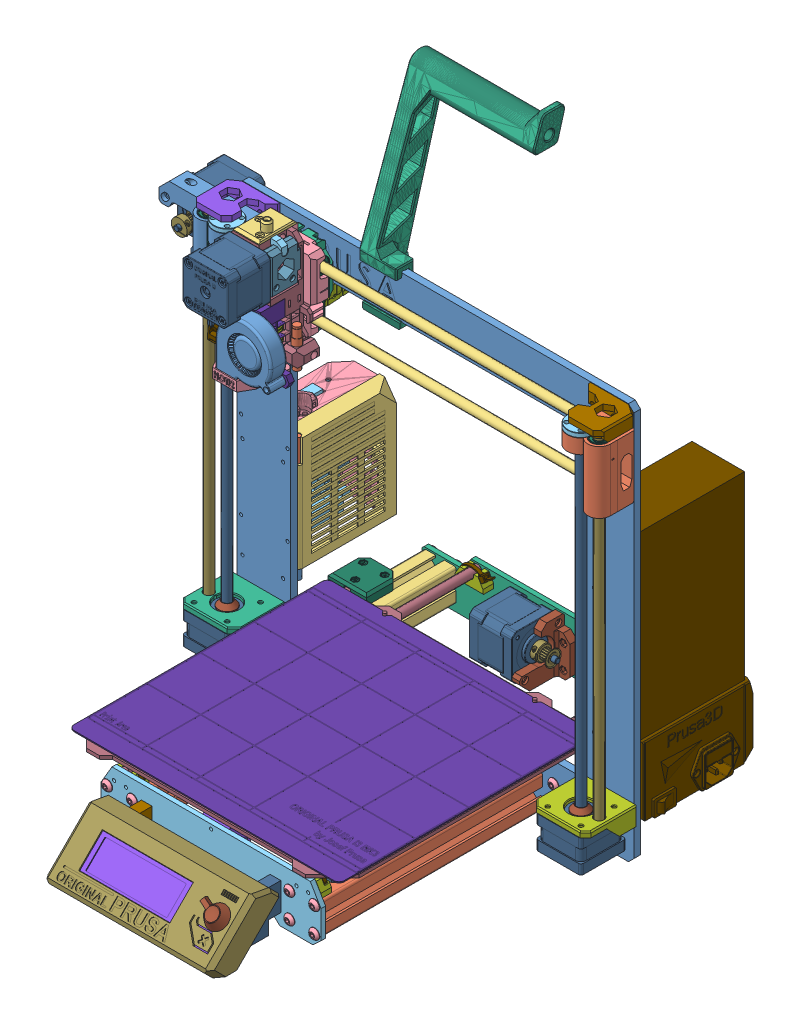
SolidWorks assembly Prusa i3 MK3, configuration Default. Lengths in mm.
Overall size (428.7 559.98 435.12).
133 component instances, 60 part files, 144 mates.
Components (placement in the parent):
- Frame Assembly-1: Frame Assembly [Default] at (46.7331 -29.8101 -38.614) size (370 375 345.6)
  - i3 MK3 Frame-1: i3 MK3 Frame [Default] at (-79.4742 52.1894 268.1135) size (370 370 6.25)
  - Long Extrusion-1: Long Extrusion [Default] at (190.5258 68.6894 274.3635) size (30 30 205)
  - Long Extrusion-2: Long Extrusion [Default] at (20.5258 68.6894 274.3635) size (30 30 205)
  - Short Extrusion-1: Short Extrusion [Default] at (-16.4742 68.6894 148.1135) size (30 30 120)
  - Short Extrusion-2: Short Extrusion [Default] at (227.5258 68.6894 148.1135) size (30 30 120)
  - M5-16 Caphead Screw-1: M5-16 Caphead Screw [92095A212] at (239.1258 57.0894 277.1135) size (9.5 9.5 19.24)
  - M5-16 Caphead Screw-2: M5-16 Caphead Screw [92095A212] at (8.9287 80.3027 486.3635) size (9.5 9.5 19.24)
  - M5-16 Caphead Screw-3: M5-16 Caphead Screw [92095A212] at (202.1295 80.303 486.3635) size (9.5 9.5 19.24)
  - M5-16 Caphead Screw-4: M5-16 Caphead Screw [92095A212] at (178.9311 80.3021 486.3635) size (9.5 9.5 19.24)
  - M5-16 Caphead Screw-5: M5-16 Caphead Screw [92095A212] at (215.9258 80.2894 277.1135) size (9.5 9.5 19.24)
  - M5-16 Caphead Screw-6: M5-16 Caphead Screw [92095A212] at (8.9258 57.0894 486.3635) size (9.5 9.5 19.24)
  - M5-16 Caphead Screw-7: M5-16 Caphead Screw [92095A212] at (178.9324 57.0896 486.3635) size (9.5 9.5 19.24)
  - M5-16 Caphead Screw-8: M5-16 Caphead Screw [92095A212] at (239.1258 80.2894 277.1135) size (9.5 9.5 19.24)
  - M5-16 Caphead Screw-9: M5-16 Caphead Screw [92095A212] at (202.1324 57.0896 486.3635) size (9.5 9.5 19.24)
  - M5-16 Caphead Screw-10: M5-16 Caphead Screw [92095A212] at (32.1258 57.0894 486.3635) size (9.5 9.5 19.24)
  - M5-16 Caphead Screw-11: M5-16 Caphead Screw [92095A212] at (32.127 80.3019 486.3635) size (9.5 9.5 19.24)
  - M5-16 Caphead Screw-12: M5-16 Caphead Screw [92095A212] at (-4.8742 80.2894 277.1135) size (9.5 9.5 19.24)
  - M5-16 Caphead Screw-13: M5-16 Caphead Screw [92095A212] at (-4.8742 57.0894 277.1135) size (9.5 9.5 19.24)
  - M5-16 Caphead Screw-14: M5-16 Caphead Screw [92095A212] at (-28.0742 80.2894 277.1135) size (9.5 9.5 19.24)
  - M5-16 Caphead Screw-15: M5-16 Caphead Screw [92095A212] at (-28.0742 57.0894 277.1135) size (9.5 9.5 19.24)
  - M5-16 Caphead Screw-16: M5-16 Caphead Screw [92095A212] at (215.9258 57.0894 277.1135) size (9.5 9.5 19.24)
  - M5-16 Caphead Screw-17: M5-16 Caphead Screw [92095A212] at (215.9258 80.2894 141.1135) x (1 0 0) z (0 0 -1) size (9.5 9.5 19.24)
  - M5-16 Caphead Screw-18: M5-16 Caphead Screw [92095A212] at (32.1258 80.2894 265.3635) x (1 0 0) z (0 0 -1) size (9.5 9.5 19.24)
  - M5-16 Caphead Screw-19: M5-16 Caphead Screw [92095A212] at (202.1258 80.2894 265.3635) x (1 0 0) z (0 0 -1) size (9.5 9.5 19.24)
  - M5-16 Caphead Screw-20: M5-16 Caphead Screw [92095A212] at (178.9258 80.2894 265.3635) x (1 0 0) z (0 0 -1) size (9.5 9.5 19.24)
  - M5-16 Caphead Screw-21: M5-16 Caphead Screw [92095A212] at (215.926 57.0893 141.1135) x (1 0 0) z (0 0 -1) size (9.5 9.5 19.24)
  - M5-16 Caphead Screw-22: M5-16 Caphead Screw [92095A212] at (8.9258 57.0894 265.3635) x (1 0 0) z (0 0 -1) size (9.5 9.5 19.24)
  - M5-16 Caphead Screw-23: M5-16 Caphead Screw [92095A212] at (8.9258 80.2894 265.3635) x (1 0 0) z (0 0 -1) size (9.5 9.5 19.24)
  - M5-16 Caphead Screw-24: M5-16 Caphead Screw [92095A212] at (239.1258 80.2894 141.1135) x (1 0 0) z (0 0 -1) size (9.5 9.5 19.24)
  - M5-16 Caphead Screw-25: M5-16 Caphead Screw [92095A212] at (239.1259 57.0892 141.1135) x (1 0 0) z (0 0 -1) size (9.5 9.5 19.24)
  - M5-16 Caphead Screw-26: M5-16 Caphead Screw [92095A212] at (-4.8712 80.276 141.1135) x (1 0 0) z (0 0 -1) size (9.5 9.5 19.24)
  - M5-16 Caphead Screw-27: M5-16 Caphead Screw [92095A212] at (-28.0743 80.2892 141.1135) x (1 0 0) z (0 0 -1) size (9.5 9.5 19.24)
  - M5-16 Caphead Screw-28: M5-16 Caphead Screw [92095A212] at (-28.072 57.0752 141.1135) x (1 0 0) z (0 0 -1) size (9.5 9.5 19.24)
  - M5-16 Caphead Screw-29: M5-16 Caphead Screw [92095A212] at (-4.874 57.0894 141.1135) x (1 0 0) z (0 0 -1) size (9.5 9.5 19.24)
  - M5-16 Caphead Screw-30: M5-16 Caphead Screw [92095A212] at (178.9258 57.0894 265.3635) x (1 0 0) z (0 0 -1) size (9.5 9.5 19.24)
  - M5-16 Caphead Screw-31: M5-16 Caphead Screw [92095A212] at (202.1258 57.0894 265.3635) x (1 0 0) z (0 0 -1) size (9.5 9.5 19.24)
  - M5-16 Caphead Screw-32: M5-16 Caphead Screw [92095A212] at (32.1258 57.0894 265.3635) x (1 0 0) z (0 0 -1) size (9.5 9.5 19.24)
  - MK3 Front Plate-1: MK3 Front Plate [Default] at (105.5324 47.1896 479.3635) x (-1 0 0) z (0 0 1) size (205 50 4.25)
  - MK3 Rear Plate-1: MK3 Rear Plate [Default] at (105.526 50.1894 143.8635) size (278 50 4.25)
- y-rod-holder(R2)-1: y-rod-holder(R2) [Default] at (67.2591 53.8793 109.4995) x (-1 0 0) z (0 0 1) size (26 13.5 10)
- y-rod-holder(R2)-2: y-rod-holder(R2) [Default] at (237.2591 53.8793 109.4995) x (-1 -0.000001 0) z (0 0 1) size (26 13.5 10)
- y-rod-holder(R2)-3: y-rod-holder(R2) [Default] at (67.2588 53.8793 440.7495) x (1 0.000003 0) z (0 0 -1) size (26 13.5 10)
- y-rod-holder(R2)-4: y-rod-holder(R2) [Default] at (237.2655 53.8796 440.7495) x (1 0 0) z (0 0 -1) size (26 13.5 10)
- y-belt-idler(R2)-1: y-belt-idler(R2) [Default] at (152.2622 27.3871 440.7495) x (-1 -0.000001 0) z (-0.000001 1 0) size (25 20 35)
- Idler Roller, flat-1: Idler Roller, flat [Default] at (147.9121 49.8871 426.7495) x (0 0 -1) z (1 0.000001 0) size (18 18 8.83)
- NEMA-17 40mm PR-1: NEMA-17 40mm PR [По умолчанию] at (99.2666 46.3725 130.4995) x (0 0 -1) z (0 -1 0) size (42.3 62 51.35)
- y-motor-holder(R2)-1: y-motor-holder(R2) [Default] at (152.2666 20.3725 110.9995) x (-1 0 0) z (0 1 0) size (19 42 47)
- PULLEY_GT2_16T-1: PULLEY_GT2_16T [Default] at (148.5591 46.3725 130.4995) x (0 -0.177583 0.984106) z (-1 0 0) size (14.7 14.7 14.3)
- Y-Smooth Rod-1: Y-Smooth Rod [Default] at (67.2588 64.3793 110.7495) size (8 8 330)
- Frog Assembly-1: Frog Assembly [Default] at (70.8506 199.1097 499.2992) x (1 0 0) z (0 0 -1) size (227 34.1 222)
  - i3 MK3 Frog-1: i3 MK3 Frog [Default] at (-100.0918 124.8902 356.7011) size (227 4.25 222)
  - LM8UU-1: LM8UU [Default] at (166.4082 134.7303 172.4511) x (0 0 -1) z (0.49499 0.868899 0) size (24 15 15)
  - LM8UU-2: LM8UU [Default] at (-3.5918 134.7303 205.9511) x (0 0 -1) z (0.957162 -0.289554 0) size (24 15 15)
  - LM8UU-3: LM8UU [Default] at (-3.5918 134.7303 135.9511) x (0 0 -1) z (-0.936768 -0.349951 0) size (24 15 15)
  - y-belt-holder(R2)-1: y-belt-holder(R2) [Default] at (88.4082 141.6402 171.2011) x (0 -1 0) z (-1 0 0) size (23.5 48 14)
  - U Bolt-1: U Bolt [Default] at (166.4082 118.7303 171.7011) size (23.09 26.7 3.46)
  - U Bolt-2: U Bolt [Default] at (-3.5918 118.7303 136.7011) size (23.09 26.7 3.46)
  - U Bolt-3: U Bolt [Default] at (-3.5918 118.7303 206.7011) size (23.09 26.7 3.46)
- Y-Smooth Rod-2: Y-Smooth Rod [Default] at (237.2655 64.3796 110.7495) size (8 8 330)
- Y Holder Ziptie-1: Y Holder Ziptie [Default] at (237.2655 53.8796 434.0495) size (30.19 10 6)
- Y Holder Ziptie-2: Y Holder Ziptie [Default] at (237.1042 53.8796 116.1995) x (1 0.000001 0) z (0 0 1) size (30.19 10 6)
- Y Holder Ziptie-3: Y Holder Ziptie [Default] at (67.4135 53.8793 434.0495) x (-1 -0.000003 0) z (0 0 -1) size (30.19 10 6)
- Y Holder Ziptie-4: Y Holder Ziptie [Default] at (67.2591 53.8793 116.1995) x (-1 0 0) z (0 0 -1) size (30.19 10 6)
- x-end-motor(R2)-1: x-end-motor(R2) [Default] at (-29.7411 380.6793 265.0495) x (0 0 1) z (0 -1 0) size (36.16 82.62 62.53)
- x-end-idler(R2)-1: x-end-idler(R2) [Default] at (355.2589 380.6793 265.0495) x (0 0 1) z (0 -1 0) size (36.12 40.12 58)
- X-Smooth Rod-1: X-Smooth Rod [Default] at (-36.7411 374.6793 250.0495) x (0 0 -1) z (1 0 0) size (8 8 370)
- X-Smooth Rod-2: X-Smooth Rod [Default] at (-36.7411 329.6793 250.0495) x (0 0 -1) z (1 0 0) size (8 8 370)
- LM8UU-1: LM8UU [Default] at (-29.7411 368.6793 265.0495) x (0 1 0) z (0 0 1) size (24 15 15)
- LM8UU-2: LM8UU [Default] at (334.2589 334.6793 265.0495) x (0 1 0) z (0 0 1) size (24 15 15)
- LM8UU-3: LM8UU [Default] at (-29.7411 335.2793 265.0495) x (0 1 0) z (0 0 1) size (24 15 15)
- LM8UU-4: LM8UU [Default] at (334.2589 368.6793 265.0495) x (0 1 0) z (-0.546944 0 0.837169) size (24 15 15)
- LM8UU-5: LM8UU [Default] at (24.8458 374.6793 250.0495) size (24 15 15)
- LM8UU-6: LM8UU [Default] at (37.3458 329.6793 250.0495) size (24 15 15)
- LM8UU-7: LM8UU [Default] at (48.8458 374.6793 250.0495) size (24 15 15)
- NEMA-17 40mm PR-2: NEMA-17 40mm PR [По умолчанию] at (-61.7411 350.4293 201.5495) x (1 0 0) z (0 -1 0) size (42.3 62 51.35)
- PULLEY_GT2_16T-2: PULLEY_GT2_16T [Default] at (-61.7411 350.4293 254.7495) x (0.994167 -0.107852 0) z (0 0 1) size (14.7 14.7 14.3)
- x-carriage(R2)-1: x-carriage(R2) [Default] at (21.3458 329.6793 262.0495) x (-1 0 0) z (0 0 -1) size (52 90 15)
- Idler Roller, flat-2: Idler Roller, flat [Default] at (318.7589 350.4293 246.6995) size (18 18 8.83)
- Z_NUT-1: Z_NUT [Default] at (-12.7411 384.6793 265.0495) x (0.707107 0 -0.707107) z (0.707107 0 0.707107) size (25 10 25)
- Z_NUT-2: Z_NUT [Default] at (317.2589 384.6793 265.0495) x (0.707107 0 0.707107) z (-0.707107 0 0.707107) size (25 10 25)
- z-axis-bottom-left(R2)-1: z-axis-bottom-left(R2) [Default] at (-45.7411 74.1793 235.7495) x (0 0 1) z (0 -1 0) size (50 52.5 36)
- z-axis-bottom-right(R2)-1: z-axis-bottom-right(R2) [Default] at (337.2589 74.1793 235.7495) x (0 0 1) z (0 -1 0) size (50 52.5 36)
- z-axis-top-left(R2)-1: z-axis-top-left(R2) [Default] at (-42.7411 392.1793 235.7495) x (0 0 1) z (0 -1 0) size (38 45 16)
- z-axis-top-right(R2)-1: z-axis-top-right(R2) [Default] at (337.2589 392.1793 235.7495) x (0 0 1) z (0 -1 0) size (38 45 16)
- MOTOR_NEMA17_W_THREADED_SHAFT-1: MOTOR_NEMA17_W_THREADED_SHAFT [Default] at (-12.7411 54.1793 265.0495) x (0 0 -1) z (0 1 0) size (47.3 42.3 350)
- MOTOR_NEMA17_W_THREADED_SHAFT-2: MOTOR_NEMA17_W_THREADED_SHAFT [Default] at (317.2589 54.1793 265.0495) x (0 0 -1) z (0 1 0) size (47.3 42.3 350)
- z-screw-cover-1: z-screw-cover [Default] at (-12.7411 71.1793 265.0495) x (1 0 0) z (0 1 0) size (16 16 5)
- z-screw-cover-2: z-screw-cover [Default] at (317.2589 71.1793 265.0495) x (1 0 0) z (0 1 0) size (16 16 5)
- Z-Smooth Rod-1: Z-Smooth Rod [Default] at (-29.7411 389.1793 265.0495) x (1 0 0) z (0 -1 0) size (8 8 320)
- Z-Smooth Rod-2: Z-Smooth Rod [Default] at (334.2589 389.1793 265.0495) x (1 0 0) z (0 -1 0) size (8 8 320)
- Extruder Assembly-1: Extruder Assembly [Default] at (24.1055 296.0339 201.1728) size (76.41 114.5 76)
  - extruder-body(R2)-1: extruder-body(R2) [Default] at (14.2402 58.6454 60.8767) x (-1 0 0) z (0 0 -1) size (63.5 95 30.5)
  - extruder-idler(R2)-1: extruder-idler(R2) [Default] at (14.2402 58.6454 59.3767) x (0 0 1) z (-1 0 0) size (28 34 17)
  - idler pulley shaft-1: idler pulley shaft [Default] at (18.2402 85.6454 62.1267) size (3 3 24)
  - NEMA-17 40mm PR-1: NEMA-17 40mm PR [По умолчанию] at (10.2402 85.6454 131.3767) x (-1 0 0) z (0 -1 0) size (42.3 62 51.35)
  - E3D V6-1: E3D V6 [Default] at (14.2402 48.5454 77.8767) x (1 0 0) z (0 -1 0) size (21.69 25.84 58.6)
  - extruder-cover(R2)-1: extruder-cover(R2) [Default] at (14.2402 58.6454 60.8767) x (-1 0 0) z (0 0 -1) size (75.15 49.75 23.94)
  - Noctua-NF-A4x10-1: Noctua-NF-A4x10 [Default] at (-12.2589 37.0799 80.8112) x (0 -1 0) z (-1 0 0) size (40.06 40.06 12.26)
  - FAN_5015_BLOWER-1: FAN_5015_BLOWER [Default] at (31.7402 38.1454 116.2767) x (0 -1 0) z (1 0 0) size (51.75 17.19 52.1)
  - PINDA Probe-1: PINDA Probe [Default] at (37.2402 32.9116 72.8767) x (1 0 0) z (0 -1 0) size (7.8 7.8 35.75)
  - filament-sensor-cover-1: filament-sensor-cover [Default] at (14.2402 58.6454 60.8767) x (-1 0 0) z (0 0 -1) size (24 11.5 36)
  - nozzle-fan-1: nozzle-fan [Default] at (14.2402 58.6454 65.3767) x (-1 0 0) z (0 0 -1) size (47.83 17 42)
  - extruder-idler-plug-1: extruder-idler-plug [Default] at (13.8402 58.6454 59.3767) x (-1 0 0) z (0 0 -1) size (10.6 10.3 5.6)
- x-carriage-back(R2)-1: x-carriage-back(R2) [Default] at (38.3458 354.6793 262.1495) x (-1 0 0) z (0 0 -1) size (52 73.5 8)
- cable-holder-1: cable-holder [Default] at (38.3458 354.6793 263.0495) x (-1 0 0) z (0 0 -1) size (10 17.91 39.5)
- LCD Assembly-1: LCD Assembly [Default] at (106.2916 -100.65 474.1347) x (1 0 0) z (0 0.707107 0.707107) size (155 84.29 80.03)
  - LCD Board-1: LCD Board [Default] at (45.5138 89.6171 111.3378) size (150 63 29.71)
  - lcd-supports1-1: lcd-supports1 [Default] at (-9.0362 59.8671 105.6378) x (0 -0.707107 0.707107) z (-1 0 0) size (65.69 47.48 20)
  - lcd-supports2-1: lcd-supports2 [Default] at (110.9738 59.8671 105.6378) x (0 -0.707107 0.707107) z (-1 0 0) size (65.69 47.48 10)
  - LCD-KNOB-1: LCD-KNOB [Default] at (104.2929 89.8433 126.2378) x (-0.386654 -0.922225 0) z (0 0 1) size (20 27.64 8.79)
  - LCD-cover-ORIGINAL-MK3(R2)-1: LCD-cover-ORIGINAL-MK3(R2) [Default] at (45.2638 108.0671 124.7378) x (1 0 0) z (0 0 -1) size (155 70 26.06)
- Headbed Assembly-1: Headbed Assembly [Default] at (88.2608 -72.955 114.9048) size (253.8 13.6 281.4)
  - MK52 Bed-1: MK52 Bed [Default] at (-64.502 153.1745 327.7347) size (253.8 6 264.25)
  - 6x6x3t spacer-1: 6x6x3t spacer [Default] at (62.498 147.1745 212.6933) size (6 6 6)
  - 6x6x3t spacer-2: 6x6x3t spacer [Default] at (62.498 147.1745 107.6933) size (6 6 6)
  - 6x6x3t spacer-3: 6x6x3t spacer [Default] at (-47.502 147.1745 317.6933) size (6 6 6)
  - 6x6x3t spacer-4: 6x6x3t spacer [Default] at (-47.502 147.1745 107.6933) x (0.97497 0 -0.222336) z (0.222336 0 0.97497) size (6 6 6)
  - 6x6x3t spacer-5: 6x6x3t spacer [Default] at (167.498 147.1745 317.6933) size (6 6 6)
  - 6x6x3t spacer-6: 6x6x3t spacer [Default] at (167.498 147.1745 212.6933) size (6 6 6)
  - 6x6x3t spacer-7: 6x6x3t spacer [Default] at (167.498 147.1745 107.6933) x (0.999855 0 0.017002) z (-0.017002 0 0.999855) size (6 6 6)
  - 6x6x3t spacer-8: 6x6x3t spacer [Default] at (62.498 147.1745 317.6933) size (6 6 6)
  - 6x6x3t spacer-9: 6x6x3t spacer [Default] at (-47.502 147.1745 212.6933) size (6 6 6)
  - heatbed-cable-cover top-1: heatbed-cable-cover top [Default] at (-46.0021 152.1745 93.2347) x (1 0 0) z (0 1 0) size (36 32 8.6)
  - heatbed-cable-cover bottom-1: heatbed-cable-cover bottom [Default] at (-46.0021 157.6745 113.2347) x (-1 0 0) z (0 -1 0) size (30 16.5 6)
  - SS Sheet-1: SS Sheet [Default] at (-63.6476 156.1745 335.43) size (252 1.01 241)
- PSU-1: PSU [Default] at (284.7589 53.8793 227.9995) x (0 0 -1) z (1 0 0) size (103 233 79.05)
- Einsy-hinges2-1: Einsy-hinges2 [Default] at (18.6589 86.1793 224.4995) x (0 0 -1) z (0 1 0) size (7.8 13.8 17)
- Einsy-hinges1-1: Einsy-hinges1 [Default] at (12.6589 201.1793 224.4995) x (0 0 -1) z (0 -1 0) size (7.4 13.4 28)
- einsey-doors-1: einsey-doors [Default] at (17.1589 201.6793 136.9995) x (0 -1 0) z (-1 0 0) size (105.5 92 16.29)
- Einsy-base-1: Einsy-base [Default] at (-32.8339 200.6796 229.4995) x (-0.000069 -1 0) z (1 -0.000069 0) size (127.5 92 38)
- Einsy_Rambo-1: Einsy_Rambo [Default] at (-23.241 175.7001 163.4002) x (-0.000069 -1 0) z (1 -0.000069 0) size (108.28 71 21.5)
- Spool-holder-1: Spool-holder [Default] at (86.205 379.5108 561.5962) x (0 0 -1) z (1 0 0) size (72.27 192.64 120.6)
Mates (geometry in assembly coordinates):
- Coincident1: coincident anti-aligned: plane of Frame Assembly-1/MK3 Front Plate-1 through (152.2655 17.3796 440.7495) normal (0 0 -1); plane of y-rod-holder(R2)-3 through (54.2588 53.8793 440.7495) normal (0 0 1)
- Coincident2: coincident anti-aligned: plane of Frame Assembly-1/MK3 Front Plate-1 through (152.2655 17.3796 440.7495) normal (0 0 -1); plane of y-rod-holder(R2)-4 through (224.2655 53.8796 440.7495) normal (0 0 1)
- Concentric1: concentric anti-aligned: circle of Frame Assembly-1/MK3 Front Plate-1; cone of y-rod-holder(R2)-4 through (242.7655 57.3796 440.7495) axis (0 0 -1)
- Concentric2: concentric aligned: circle of Frame Assembly-1/MK3 Front Plate-1; circle of y-rod-holder(R2)-4
- Concentric3: concentric aligned: circle of Frame Assembly-1/MK3 Front Plate-1; circle of y-rod-holder(R2)-3
- Concentric4: concentric aligned: circle of Frame Assembly-1/MK3 Front Plate-1; circle of y-rod-holder(R2)-3
- Coincident4: coincident anti-aligned: plane of Frame Assembly-1/MK3 Rear Plate-1 through (152.2591 20.3793 109.4995) normal (0 0 1); plane of y-rod-holder(R2)-2 through (250.2591 53.8794 109.4995) normal (0 0 -1)
- Coincident5: coincident anti-aligned: plane of Frame Assembly-1/MK3 Rear Plate-1 through (152.2591 20.3793 109.4995) normal (0 0 1); plane of y-rod-holder(R2)-1 through (80.2591 53.8793 109.4995) normal (0 0 -1)
- Concentric5: concentric anti-aligned: circle of Frame Assembly-1/MK3 Rear Plate-1; cylinder of y-rod-holder(R2)-1 through (61.7591 57.3793 118.4995) axis (0 0 -1) radius 1.6
- Concentric9: concentric aligned: cylinder of Frame Assembly-1/MK3 Rear Plate-1 through (231.7591 57.3793 109.4995) axis (0 0 -1) radius 1.5; circle of y-rod-holder(R2)-2
- Concentric10: concentric aligned: cylinder of Frame Assembly-1/MK3 Rear Plate-1 through (242.7591 57.3793 109.4995) axis (0 0 -1) radius 1.5; circle of y-rod-holder(R2)-2
- Parallel1: parallel aligned: plane of Frame Assembly-1/MK3 Rear Plate-1 through (245.2591 67.3793 109.4995) normal (0 1 0); plane of y-rod-holder(R2)-1 through (80.2591 65.8793 109.4995) normal (0 1 0)
- Coincident7: coincident anti-aligned: plane of y-belt-idler(R2)-1 through (152.2622 27.3871 440.7495) normal (-1 -0.000001 0); plane of Idler Roller, flat-1 through (152.2621 49.8871 426.7495) normal (1 0.000001 0)
- Concentric11: concentric anti-aligned: cylinder of y-belt-idler(R2)-1 through (144.2621 49.8871 426.7495) axis (-1 -0.000001 0) radius 3.1; cylinder of Idler Roller, flat-1 through (147.9111 49.8871 426.7495) axis (1 0.000001 0) radius 2.5
- Coincident8: coincident anti-aligned: plane of Frame Assembly-1/MK3 Front Plate-1 through (152.2655 17.3796 440.7495) normal (0 0 -1); plane of y-belt-idler(R2)-1 through (164.7622 32.3871 440.7495) normal (0 0 1)
- Concentric12: concentric aligned: circle of Frame Assembly-1/MK3 Front Plate-1; circle of y-belt-idler(R2)-1
- Concentric13: concentric anti-aligned: cylinder of Frame Assembly-1/MK3 Front Plate-1 through (152.2622 37.387 444.9995) axis (0 0 -1) radius 1.5; circle of y-belt-idler(R2)-1
- Coincident9: coincident anti-aligned: plane of NEMA-17 40mm PR-1 through (139.2666 46.3725 130.4995) normal (1 0 0); plane of y-motor-holder(R2)-1 through (139.2666 20.3725 109.4995) normal (-1 0 0)
- Concentric14: concentric aligned: circle of NEMA-17 40mm PR-1; cylinder of y-motor-holder(R2)-1 through (148.2666 61.8725 114.9995) axis (-1 0 0) radius 3.1
- Concentric15: concentric aligned: circle of NEMA-17 40mm PR-1; circle of y-motor-holder(R2)-1
- Coincident10: coincident anti-aligned: plane of Frame Assembly-1/MK3 Rear Plate-1 through (152.2591 20.3793 109.4995) normal (0 0 1); plane of y-motor-holder(R2)-1 through (158.2666 20.3725 109.4995) normal (0 0 -1)
- Concentric16: concentric anti-aligned: circle of Frame Assembly-1/MK3 Rear Plate-1; cylinder of y-motor-holder(R2)-1 through (152.2666 27.3725 122.9995) axis (0 0 -1) radius 1.6
- Parallel2: parallel aligned: plane of Frame Assembly-1/MK3 Rear Plate-1 through (245.2591 67.3793 109.4995) normal (0 1 0); plane of y-motor-holder(R2)-1 through (158.2666 67.3725 109.4995) normal (0 1 0)
- Concentric19: concentric anti-aligned: cylinder of NEMA-17 40mm PR-1 through (161.2666 46.3725 130.4995) axis (-1 0 0) radius 2.5; cylinder of PULLEY_GT2_16T-1 through (142.2591 46.3725 130.4995) axis (1 0 0) radius 2.5
- Coincident15: coincident aligned: plane of Frame Assembly-1/MK3 Rear Plate-1 through (152.2591 20.3793 105.2495) normal (1 0 0); plane of PULLEY_GT2_16T-1 through (152.2591 46.3725 130.4995) normal (1 0 0)
- Concentric20: concentric anti-aligned: cylinder of y-rod-holder(R2)-3 through (67.2588 64.3793 429.7495) axis (0 0 1) radius 4; cylinder of Y-Smooth Rod-1 through (67.2588 64.3793 440.7495) axis (0 0 -1) radius 4
- Coincident16: coincident anti-aligned: plane of Frame Assembly-1/MK3 Front Plate-1 through (152.2655 17.3796 440.7495) normal (0 0 -1); plane of Y-Smooth Rod-1 through (67.2588 64.3793 440.7495) normal (0 0 1)
- Concentric21: concentric anti-aligned: cylinder of y-rod-holder(R2)-4 through (237.2655 64.3796 429.7495) axis (0 0 1) radius 4; cylinder of Y-Smooth Rod-2 through (237.2655 64.3796 440.7495) axis (0 0 -1) radius 4
- Coincident17: coincident anti-aligned: plane of Frame Assembly-1/MK3 Front Plate-1 through (152.2655 17.3796 440.7495) normal (0 0 -1); plane of Y-Smooth Rod-2 through (237.2655 64.3796 440.7495) normal (0 0 1)
- Concentric22: concentric aligned: cylinder of Y-Smooth Rod-1 through (67.2588 64.3793 440.7495) axis (0 0 -1) radius 4; cylinder of Frog Assembly-1/LM8UU-3 through (67.2588 64.3793 317.6586) axis (0 0 -1) radius 4
- Parallel3: parallel aligned: plane of Frame Assembly-1/i3 MK3 Frame-1 through (-32.7411 58.8793 235.7495) normal (0 1 0); plane of Frog Assembly-1/i3 MK3 Frog-1 through (-29.2412 74.2195 142.5981) normal (0 1 0)
- Tangent2: tangent aligned: cylinder of Y-Smooth Rod-2 through (237.2655 64.3796 440.7495) axis (0 0 -1) radius 4; cylinder of Y Holder Ziptie-1 through (237.3428 54.524 435.5495) axis (0 0 -1) radius 13.8558
- Coincident20: coincident anti-aligned: plane of y-rod-holder(R2)-4 through (238.0655 78.3796 435.5495) normal (0.866025 0.5 0); plane of Y Holder Ziptie-1 through (248.4743 60.351 435.5495) normal (-0.866025 -0.5 0)
- Coincident21: coincident anti-aligned: plane of y-rod-holder(R2)-4 through (245.0655 62.8796 435.5495) normal (0 0 -1); plane of Y Holder Ziptie-1 through (237.2655 53.8796 435.5495) normal (0 0 1)
- Coincident22: coincident anti-aligned: plane of y-rod-holder(R2)-3 through (67.1908 79.3793 435.5495) normal (-0.866027 0.499998 0); plane of Y Holder Ziptie-3 through (56.2047 60.3507 432.5495) normal (0.866027 -0.499998 0)
- Coincident23: coincident anti-aligned: plane of y-rod-holder(R2)-3 through (75.0588 62.8794 435.5495) normal (0 0 -1); plane of Y Holder Ziptie-3 through (67.4135 53.8793 435.5495) normal (0 0 1)
- Tangent3: tangent aligned: cylinder of Y-Smooth Rod-1 through (67.2588 64.3793 440.7495) axis (0 0 -1) radius 4; cylinder of Y Holder Ziptie-3 through (67.3361 54.5238 432.5495) axis (0 0 1) radius 13.8558
- Tangent4: tangent aligned: cylinder of Y-Smooth Rod-1 through (67.2588 64.3793 440.7495) axis (0 0 -1) radius 4; cylinder of Y Holder Ziptie-4 through (67.1817 54.5238 114.6995) axis (0 0 1) radius 13.8558
- Tangent5: tangent aligned: cylinder of Y-Smooth Rod-2 through (237.2655 64.3796 440.7495) axis (0 0 -1) radius 4; cylinder of Y Holder Ziptie-2 through (237.1816 54.5241 117.6995) axis (0 0 -1) radius 13.8558
- Coincident24: coincident anti-aligned: plane of y-rod-holder(R2)-1 through (66.4591 78.3793 114.6995) normal (-0.866025 0.5 0); plane of Y Holder Ziptie-4 through (56.0503 60.3507 114.6995) normal (0.866025 -0.5 0)
- Coincident25: coincident anti-aligned: plane of y-rod-holder(R2)-1 through (59.4591 62.8793 114.6995) normal (0 0 1); plane of Y Holder Ziptie-4 through (67.2591 53.8793 114.6995) normal (0 0 -1)
- Coincident26: coincident anti-aligned: plane of y-rod-holder(R2)-2 through (237.327 79.3793 114.6995) normal (0.866025 0.500001 0); plane of Y Holder Ziptie-2 through (248.313 60.351 117.6995) normal (-0.866025 -0.500001 0)
- Coincident27: coincident anti-aligned: plane of y-rod-holder(R2)-2 through (229.4591 62.8793 114.6995) normal (0 0 1); plane of Y Holder Ziptie-2 through (237.1042 53.8796 114.6995) normal (0 0 -1)
- Concentric23: concentric anti-aligned: cylinder of x-end-idler(R2)-1 through (292.7589 329.6793 250.0495) axis (1 0 0) radius 4.0764; cylinder of X-Smooth Rod-2 through (333.2589 329.6793 250.0495) axis (-1 0 0) radius 4
- Concentric24: concentric anti-aligned: cylinder of x-end-idler(R2)-1 through (293.2589 374.6793 250.0495) axis (1 0 0) radius 4.0764; cylinder of X-Smooth Rod-1 through (333.2589 374.6793 250.0495) axis (-1 0 0) radius 4
- Coincident28: coincident aligned: plane of X-Smooth Rod-1 through (-36.7411 374.6793 250.0495) normal (-1 0 0); plane of X-Smooth Rod-2 through (-36.7411 329.6793 250.0495) normal (-1 0 0)
- Concentric25: concentric aligned: cylinder of x-end-motor(R2)-1 through (11.2589 374.6793 250.0495) axis (-1 0 0) radius 4.0764; cylinder of X-Smooth Rod-1 through (333.2589 374.6793 250.0495) axis (-1 0 0) radius 4
- Coincident29: coincident anti-aligned: plane of x-end-idler(R2)-1 through (333.2589 374.6793 250.0495) normal (-1 0 0); plane of X-Smooth Rod-1 through (333.2589 374.6793 250.0495) normal (1 0 0)
- Concentric27: concentric aligned: cylinder of LM8UU-1 through (-29.7411 322.9898 265.0495) axis (0 -1 0) radius 7.5; cylinder of LM8UU-3 through (-29.7411 289.5898 265.0495) axis (0 -1 0) radius 7.5
- Concentric28: concentric aligned: cylinder of LM8UU-2 through (334.2589 288.9898 265.0495) axis (0 -1 0) radius 7.5; cylinder of LM8UU-4 through (334.2589 322.9898 265.0495) axis (0 -1 0) radius 7.5
- Concentric29: concentric aligned: cylinder of x-end-motor(R2)-1 through (-29.7411 381.6793 265.0495) axis (0 -1 0) radius 7.5408; cylinder of LM8UU-3 through (-29.7411 289.5898 265.0495) axis (0 -1 0) radius 7.5
- Coincident30: coincident aligned: circle of x-end-motor(R2)-1; plane of LM8UU-3 through (-29.7411 323.2793 265.0495) normal (0 -1 0)
- Coincident31: coincident aligned: plane of x-end-motor(R2)-1 through (-29.7411 380.6793 265.0495) normal (0 1 0); plane of LM8UU-1 through (-29.7411 380.6793 265.0495) normal (0 1 0)
- Concentric30: concentric aligned: cylinder of x-end-idler(R2)-1 through (334.2589 381.6793 265.0495) axis (0 -1 0) radius 7.5408; cylinder of LM8UU-2 through (334.2589 288.9898 265.0495) axis (0 -1 0) radius 7.5
- Coincident32: coincident aligned: plane of x-end-idler(R2)-1 through (334.2589 322.6793 265.0495) normal (0 -1 0); plane of LM8UU-2 through (334.2589 322.6793 265.0495) normal (0 -1 0)
- Coincident33: coincident aligned: plane of x-end-idler(R2)-1 through (334.2589 380.6793 265.0495) normal (0 1 0); plane of LM8UU-4 through (334.2589 380.6793 265.0495) normal (0 1 0)
- Concentric31: concentric anti-aligned: circle of x-end-motor(R2)-1; cylinder of X-Smooth Rod-2 through (333.2589 329.6793 250.0495) axis (-1 0 0) radius 4
- Concentric32: concentric aligned: cylinder of X-Smooth Rod-1 through (333.2589 374.6793 250.0495) axis (-1 0 0) radius 4; cylinder of LM8UU-5 through (-20.8438 374.6793 250.0495) axis (-1 0 0) radius 7.5
- Concentric33: concentric aligned: cylinder of X-Smooth Rod-1 through (333.2589 374.6793 250.0495) axis (-1 0 0) radius 4; cylinder of LM8UU-7 through (3.1562 374.6793 250.0495) axis (-1 0 0) radius 7.5
- Concentric34: concentric aligned: cylinder of X-Smooth Rod-2 through (333.2589 329.6793 250.0495) axis (-1 0 0) radius 4; cylinder of LM8UU-6 through (-8.3438 329.6793 250.0495) axis (-1 0 0) radius 7.5
- Concentric35: concentric aligned: cylinder of NEMA-17 40mm PR-2 through (-61.7411 350.4293 263.5495) axis (0 0 -1) radius 2.5; cylinder of PULLEY_GT2_16T-2 through (-61.7411 350.4293 261.0495) axis (0 0 -1) radius 7.35
- Coincident34: coincident anti-aligned: plane of x-end-motor(R2)-1 through (-1.2411 380.6793 241.5495) normal (0 0 -1); plane of NEMA-17 40mm PR-2 through (-61.7411 350.4293 241.5495) normal (0 0 1)
- Concentric36: concentric aligned: cone of x-end-motor(R2)-1 through (-46.2411 334.9293 255.0495) axis (0 0 -1); cylinder of NEMA-17 40mm PR-2 through (-46.2411 334.9293 241.5495) axis (0 0 -1) radius 1.25
- Parallel4: parallel aligned: plane of x-end-motor(R2)-1 through (-29.7411 380.6793 265.0495) normal (0 1 0); plane of NEMA-17 40mm PR-2 through (-76.1646 371.5793 233.5495) normal (0 1 0)
- Parallel5: parallel aligned: plane of Frame Assembly-1/i3 MK3 Frame-1 through (-32.7411 392.3793 235.7495) normal (0 1 0); plane of x-end-motor(R2)-1 through (-29.7411 380.6793 265.0495) normal (0 1 0)
- Coincident35: coincident anti-aligned: plane of LM8UU-5 through (36.8458 374.6793 250.0495) normal (1 0 0); plane of LM8UU-7 through (36.8458 374.6793 250.0495) normal (-1 0 0)
- Concentric37: concentric aligned: cylinder of LM8UU-5 through (-20.8438 374.6793 250.0495) axis (-1 0 0) radius 7.5; cylinder of x-carriage(R2)-1 through (67.8458 374.6793 250.0495) axis (-1 0 0) radius 7.675
- Concentric38: concentric aligned: cylinder of LM8UU-6 through (-8.3438 329.6793 250.0495) axis (-1 0 0) radius 7.5; cylinder of x-carriage(R2)-1 through (55.3458 329.6793 250.0495) axis (-1 0 0) radius 7.675
- Coincident36: coincident anti-aligned: plane of LM8UU-6 through (25.3458 329.6793 250.0495) normal (-1 0 0); plane of x-carriage(R2)-1 through (25.3458 317.6793 263.0495) normal (1 0 0)
- Coincident37: coincident anti-aligned: plane of LM8UU-5 through (12.8458 374.6793 250.0495) normal (-1 0 0); plane of x-carriage(R2)-1 through (12.8458 362.6793 263.0495) normal (1 0 0)
- Concentric39: concentric anti-aligned: cylinder of x-end-idler(R2)-1 through (318.7589 350.4293 265.0495) axis (0 0 -1) radius 1.55; cylinder of Idler Roller, flat-2 through (318.7589 350.4293 246.6985) axis (0 0 1) radius 2.5
- Coincident38: coincident aligned: plane of x-end-idler(R2)-1 through (355.2589 380.6793 251.0495) normal (0 0 1); plane of Idler Roller, flat-2 through (318.7589 350.4293 251.0495) normal (0 0 1)
- Coincident39: coincident anti-aligned: plane of x-end-motor(R2)-1 through (-29.7411 380.6793 265.0495) normal (0 1 0); plane of Z_NUT-1 through (-12.7411 380.6793 265.0495) normal (0 -1 0)
- Concentric40: concentric aligned: cylinder of x-end-motor(R2)-1 through (-12.7411 381.6793 265.0495) axis (0 -1 0) radius 6.7; cylinder of Z_NUT-1 through (-12.7411 385.1793 265.0495) axis (0 -1 0) radius 4
- Concentric41: concentric aligned: circle of x-end-motor(R2)-1; cylinder of Z_NUT-1 through (-6.0236 384.6793 271.767) axis (0 1 0) radius 2
- Coincident40: coincident anti-aligned: plane of x-end-idler(R2)-1 through (334.2589 380.6793 265.0495) normal (0 1 0); plane of Z_NUT-2 through (317.2589 380.6793 265.0495) normal (0 -1 0)
- Concentric42: concentric aligned: cylinder of x-end-idler(R2)-1 through (317.2589 381.6793 265.0495) axis (0 -1 0) radius 6.7; cylinder of Z_NUT-2 through (317.2589 385.1793 265.0495) axis (0 -1 0) radius 4
- Concentric43: concentric anti-aligned: cylinder of x-end-idler(R2)-1 through (310.5414 384.6793 271.767) axis (0 -1 0) radius 1.65; cylinder of Z_NUT-2 through (310.5414 384.6793 271.767) axis (0 1 0) radius 2
- Coincident41: coincident anti-aligned: plane of Frame Assembly-1/i3 MK3 Frame-1 through (-32.7411 22.3793 235.7495) normal (0 0 1); plane of z-axis-bottom-left(R2)-1 through (-34.2411 74.1793 235.7495) normal (0 0 -1)
- Coincident42: coincident anti-aligned: plane of Frame Assembly-1/i3 MK3 Frame-1 through (-32.7411 22.3793 235.7495) normal (0 0 1); plane of z-axis-bottom-right(R2)-1 through (338.7589 74.1793 235.7495) normal (0 0 -1)
- Coincident43: coincident anti-aligned: plane of Frame Assembly-1/i3 MK3 Frame-1 through (-32.7411 22.3793 235.7495) normal (0 0 1); plane of z-axis-top-left(R2)-1 through (-37.7411 392.1793 235.7495) normal (0 0 -1)
- Coincident44: coincident anti-aligned: plane of Frame Assembly-1/i3 MK3 Frame-1 through (-32.7411 22.3793 235.7495) normal (0 0 1); plane of z-axis-top-right(R2)-1 through (342.2589 392.1793 235.7495) normal (0 0 -1)
- Concentric44: concentric aligned: cylinder of Frame Assembly-1/i3 MK3 Frame-1 through (-12.7411 42.1793 235.7495) axis (0 0 -1) radius 1.5; circle of z-axis-bottom-left(R2)-1
- Concentric45: concentric aligned: cylinder of Frame Assembly-1/i3 MK3 Frame-1 through (-22.7411 62.1793 235.7495) axis (0 0 -1) radius 1.5; circle of z-axis-bottom-left(R2)-1
- Concentric46: concentric aligned: circle of Frame Assembly-1/i3 MK3 Frame-1; cylinder of z-axis-bottom-right(R2)-1 through (317.2589 42.1793 234.7495) axis (0 0 1) radius 1.6
- Concentric47: concentric aligned: cylinder of Frame Assembly-1/i3 MK3 Frame-1 through (307.2589 62.1793 235.7495) axis (0 0 -1) radius 1.5; circle of z-axis-bottom-right(R2)-1
- Concentric48: concentric aligned: circle of Frame Assembly-1/i3 MK3 Frame-1; circle of z-axis-top-left(R2)-1
- Concentric49: concentric anti-aligned: cylinder of Frame Assembly-1/i3 MK3 Frame-1 through (-2.7411 382.1793 235.7495) axis (0 0 -1) radius 1.5; cylinder of z-axis-top-left(R2)-1 through (-2.7411 382.1793 234.7495) axis (0 0 1) radius 1.6
- Concentric50: concentric anti-aligned: circle of Frame Assembly-1/i3 MK3 Frame-1; circle of z-axis-top-right(R2)-1
- Concentric51: concentric anti-aligned: cylinder of Frame Assembly-1/i3 MK3 Frame-1 through (327.2589 382.1793 235.7495) axis (0 0 -1) radius 1.5; cylinder of z-axis-top-right(R2)-1 through (327.2589 382.1793 234.7495) axis (0 0 1) radius 1.6
- Coincident45: coincident anti-aligned: plane of z-axis-bottom-left(R2)-1 through (-37.7411 69.1793 235.7495) normal (0 -1 0); plane of MOTOR_NEMA17_W_THREADED_SHAFT-1 through (-12.7411 69.1793 265.0495) normal (0 1 0)
- Concentric52: concentric anti-aligned: circle of z-axis-bottom-left(R2)-1; cylinder of MOTOR_NEMA17_W_THREADED_SHAFT-1 through (-28.2411 69.1793 280.5495) axis (0 1 0) radius 1.5
- Concentric53: concentric aligned: cylinder of z-axis-bottom-left(R2)-1 through (2.7589 76.1793 249.5495) axis (0 -1 0) radius 1.65; circle of MOTOR_NEMA17_W_THREADED_SHAFT-1
- Coincident46: coincident anti-aligned: plane of z-axis-bottom-right(R2)-1 through (342.2589 69.1793 235.7495) normal (0 -1 0); plane of MOTOR_NEMA17_W_THREADED_SHAFT-2 through (317.2589 69.1793 265.0495) normal (0 1 0)
- Concentric54: concentric aligned: cylinder of z-axis-bottom-right(R2)-1 through (301.7589 76.1793 280.5495) axis (0 -1 0) radius 1.65; circle of MOTOR_NEMA17_W_THREADED_SHAFT-2
- Concentric55: concentric aligned: cylinder of z-axis-bottom-right(R2)-1 through (332.7589 76.1793 249.5495) axis (0 -1 0) radius 1.65; circle of MOTOR_NEMA17_W_THREADED_SHAFT-2
- Concentric56: concentric aligned: cylinder of MOTOR_NEMA17_W_THREADED_SHAFT-1 through (-12.7411 69.1793 265.0495) axis (0 1 0) radius 4; cylinder of z-screw-cover-1 through (-12.7411 70.1793 265.0495) axis (0 1 0) radius 4.2
- Coincident47: coincident anti-aligned: plane of MOTOR_NEMA17_W_THREADED_SHAFT-1 through (-12.7411 71.1793 265.0495) normal (0 1 0); plane of z-screw-cover-1 through (-12.7411 71.1793 265.0495) normal (0 -1 0)
- Concentric57: concentric aligned: cylinder of MOTOR_NEMA17_W_THREADED_SHAFT-2 through (317.2589 69.1793 265.0495) axis (0 1 0) radius 4; cylinder of z-screw-cover-2 through (317.2589 70.1793 265.0495) axis (0 1 0) radius 4.2
- Coincident48: coincident anti-aligned: plane of MOTOR_NEMA17_W_THREADED_SHAFT-2 through (317.2589 71.1793 265.0495) normal (0 1 0); plane of z-screw-cover-2 through (317.2589 71.1793 265.0495) normal (0 -1 0)
- Concentric58: concentric anti-aligned: cylinder of z-axis-bottom-left(R2)-1 through (-29.7411 75.1793 265.0495) axis (0 -1 0) radius 4.05; cylinder of Z-Smooth Rod-1 through (-29.7411 69.1793 265.0495) axis (0 1 0) radius 4
- Concentric59: concentric anti-aligned: cylinder of z-axis-bottom-right(R2)-1 through (334.2589 75.1793 265.0495) axis (0 -1 0) radius 4.05; cylinder of Z-Smooth Rod-2 through (334.2589 69.1793 265.0495) axis (0 1 0) radius 4
- Coincident49: coincident anti-aligned: plane of MOTOR_NEMA17_W_THREADED_SHAFT-2 through (317.2589 69.1793 265.0495) normal (0 1 0); plane of Z-Smooth Rod-2 through (334.2589 69.1793 265.0495) normal (0 -1 0)
- Coincident50: coincident anti-aligned: plane of MOTOR_NEMA17_W_THREADED_SHAFT-1 through (-12.7411 69.1793 265.0495) normal (0 1 0); plane of Z-Smooth Rod-1 through (-29.7411 69.1793 265.0495) normal (0 -1 0)
- Concentric60: concentric anti-aligned: circle of LM8UU-1; cylinder of Z-Smooth Rod-1 through (-29.7411 69.1793 265.0495) axis (0 1 0) radius 4
- Concentric61: concentric anti-aligned: cylinder of LM8UU-4 through (334.2589 322.9898 265.0495) axis (0 -1 0) radius 4; cylinder of Z-Smooth Rod-2 through (334.2589 69.1793 265.0495) axis (0 1 0) radius 4
- Coincident51: coincident anti-aligned: plane of PULLEY_GT2_16T-2 through (-61.7411 350.4293 251.0495) normal (0 0 -1); plane of Idler Roller, flat-2 through (318.7589 350.4293 251.0495) normal (0 0 1)
- Coincident52: coincident anti-aligned: plane of x-carriage(R2)-1 through (63.8458 382.6793 262.0495) normal (0 0 1); plane of Extruder Assembly-1/extruder-body(R2)-1 through (55.3458 318.1793 262.0495) normal (0 0 -1)
- Concentric62: concentric aligned: cylinder of x-carriage(R2)-1 through (18.8458 397.1793 312.0495) axis (0 0 -1) radius 1.8; cylinder of ? through (18.8458 397.1793 302.0495) axis (0 0 -1) radius 1.65
- Concentric63: concentric anti-aligned: cylinder of x-carriage(R2)-1 through (26.8458 354.1793 263.0495) axis (0 0 -1) radius 1.65; circle of ?
- Coincident53: coincident anti-aligned: plane of x-carriage(R2)-1 through (63.8458 382.6793 247.0495) normal (0 0 -1); plane of x-carriage-back(R2)-1 through (54.3458 315.6793 247.0495) normal (0 0 1)
- Concentric64: concentric anti-aligned: circle of x-carriage(R2)-1; cylinder of x-carriage-back(R2)-1 through (25.3458 385.6793 252.1495) axis (0 0 -1) radius 1.65
- Concentric65: concentric anti-aligned: cylinder of x-carriage(R2)-1 through (48.8458 385.6793 262.0495) axis (0 0 -1) radius 1.7; circle of x-carriage-back(R2)-1
- Coincident54: coincident anti-aligned: plane of x-carriage-back(R2)-1 through (54.3458 315.6793 239.0495) normal (0 0 -1); plane of cable-holder-1 through (42.8458 328.6793 239.0495) normal (0 0 1)
- Concentric66: concentric anti-aligned: circle of x-carriage-back(R2)-1; cylinder of cable-holder-1 through (37.8458 327.6793 199.5495) axis (0 0 -1) radius 1.75
- Parallel6: parallel aligned: plane of Frame Assembly-1/i3 MK3 Frame-1 through (-32.7411 22.3793 235.7495) normal (-1 0 0); plane of cable-holder-1 through (37.8458 354.6793 263.0495) normal (-1 0 0)
- Coincident55: coincident anti-aligned: plane of Frame Assembly-1/MK3 Front Plate-1 through (152.2655 17.3796 444.9995) normal (0 0 1); plane of LCD Assembly-1/lcd-supports2-1 through (218.2654 14.3796 444.9995) normal (0 0 -1)
- Concentric68: concentric anti-aligned: circle of Frame Assembly-1/MK3 Front Plate-1; circle of LCD Assembly-1/lcd-supports2-1
- Parallel7: parallel aligned: plane of Frame Assembly-1/MK3 Front Plate-1 through (244.7655 67.3796 444.9995) normal (0 1 0); plane of LCD Assembly-1/lcd-supports1-1 through (97.2554 54.3796 434.4995) normal (0 1 0)
- Coincident56: coincident anti-aligned: plane of Frog Assembly-1/i3 MK3 Frog-1 through (-29.2412 74.2195 142.5981) normal (0 1 0); plane of Headbed Assembly-1/6x6x3t spacer-5 through (255.7588 74.2195 432.5981) normal (0 -1 0)
- Concentric73: concentric anti-aligned: cylinder of Frog Assembly-1/i3 MK3 Frog-1 through (255.7588 69.9695 432.5981) axis (0 1 0) radius 1.5; circle of Headbed Assembly-1/6x6x3t spacer-5
- Concentric74: concentric aligned: circle of Frog Assembly-1/i3 MK3 Frog-1; circle of Headbed Assembly-1/6x6x3t spacer-4
- Coincident57: coincident anti-aligned: plane of Frame Assembly-1/Short Extrusion-2 through (274.2589 53.8793 229.4995) normal (0 1 0); plane of PSU-1 through (284.7589 53.8793 227.9995) normal (0 -1 0)
- Coincident58: coincident anti-aligned: plane of Frame Assembly-1/i3 MK3 Frame-1 through (-32.7411 22.3793 229.4995) normal (0 0 -1); plane of PSU-1 through (286.7589 83.8793 229.4995) normal (0 0 1)
- Coincident59: coincident anti-aligned: plane of Frame Assembly-1/Short Extrusion-2 through (274.2589 38.8793 109.4995) normal (1 0 0); plane of PSU-1 through (274.2589 53.8793 227.9995) normal (-1 0 0)
- Concentric75: concentric aligned: cylinder of Frame Assembly-1/i3 MK3 Frame-1 through (10.1589 90.1793 235.7495) axis (0 0 -1) radius 1.5; cylinder of Einsy-hinges2-1 through (10.1589 90.1793 236.4995) axis (0 0 -1) radius 1.75
- Coincident60: coincident anti-aligned: plane of Frame Assembly-1/i3 MK3 Frame-1 through (-32.7411 22.3793 229.4995) normal (0 0 -1); plane of Einsy-hinges2-1 through (12.6589 86.1793 229.4995) normal (0 0 1)
- Coincident61: coincident anti-aligned: plane of Frame Assembly-1/i3 MK3 Frame-1 through (-32.7411 22.3793 229.4995) normal (0 0 -1); plane of Einsy-hinges1-1 through (1.6589 201.1793 229.4995) normal (0 0 1)
- Concentric76: concentric aligned: cylinder of Frame Assembly-1/i3 MK3 Frame-1 through (10.1589 184.1793 235.7495) axis (0 0 -1) radius 1.5; cylinder of Einsy-hinges1-1 through (10.1589 184.1793 236.9995) axis (0 0 -1) radius 1.75
- Concentric77: concentric anti-aligned: cylinder of Einsy-hinges1-1 through (12.6589 201.1793 224.4995) axis (0 -1 0) radius 2.4; cylinder of einsey-doors-1 through (12.6589 175.1793 224.4995) axis (0 1 0) radius 2.6
- Concentric78: concentric aligned: cylinder of Einsy-hinges2-1 through (12.6589 86.1793 224.4995) axis (0 1 0) radius 2.4; circle of einsey-doors-1
- Coincident62: coincident anti-aligned: plane of Einsy-hinges2-1 through (12.6589 96.1793 229.4995) normal (0 1 0); plane of einsey-doors-1 through (12.6589 96.1793 224.4995) normal (0 -1 0)
- Coincident63: coincident anti-aligned: plane of Frame Assembly-1/i3 MK3 Frame-1 through (-32.7411 22.3793 229.4995) normal (0 0 -1); plane of Einsy-base-1 through (-32.8339 200.6796 229.4995) normal (0 0 1)
- Concentric79: concentric aligned: circle of Frame Assembly-1/i3 MK3 Frame-1; circle of Einsy-base-1
- Concentric80: concentric anti-aligned: cylinder of Frame Assembly-1/i3 MK3 Frame-1 through (-27.8411 90.1793 235.7495) axis (0 0 -1) radius 1.5; circle of Einsy-base-1
- Coincident64: coincident anti-aligned: plane of Einsy-base-1 through (-24.8339 200.6791 229.4995) normal (1 -0.000069 0); plane of Einsy_Rambo-1 through (-24.8341 198.1792 220.4992) normal (-1 0.000069 0)
- Concentric81: concentric aligned: circle of Einsy-base-1; circle of Einsy_Rambo-1
- Concentric82: concentric aligned: circle of Einsy-base-1; circle of Einsy_Rambo-1
- Parallel8: parallel aligned: plane of Frame Assembly-1/i3 MK3 Frame-1 through (-32.7411 22.3793 229.4995) normal (0 0 -1); plane of einsey-doors-1 through (17.1589 201.6793 136.9995) normal (0 0 -1)
- Coincident66: coincident anti-aligned: plane of Frame Assembly-1/i3 MK3 Frame-1 through (-32.7411 22.3793 229.4995) normal (0 0 -1); plane of Spool-holder-1 through (86.205 379.5108 229.4995) normal (0 0 1)
- Coincident67: coincident anti-aligned: plane of Frame Assembly-1/i3 MK3 Frame-1 through (-32.7411 392.3793 235.7495) normal (0 1 0); plane of Spool-holder-1 through (86.205 392.3793 561.5962) normal (0 -1 0)
- LimitDistance1: limit distance = 0 mm anti-aligned: plane of Z_NUT-1 through (-12.7411 384.6793 265.0495) normal (0 1 0); plane of z-axis-top-left(R2)-1 through (-29.5411 384.6793 265.0495) normal (0 -1 0)
- LimitDistance2: limit distance = 13.0869 mm anti-aligned: plane of x-carriage(R2)-1 through (11.8458 348.6793 263.0495) normal (-1 0 0); plane of x-end-motor(R2)-1 through (-1.2411 380.6793 241.5495) normal (1 0 0)
- LimitDistance3: limit distance = 161.8487 mm anti-aligned: plane of Frog Assembly-1/LM8UU-2 through (67.2588 64.3793 281.3481) normal (0 0 -1); plane of y-rod-holder(R2)-1 through (80.2591 53.8793 119.4995) normal (0 0 1)
